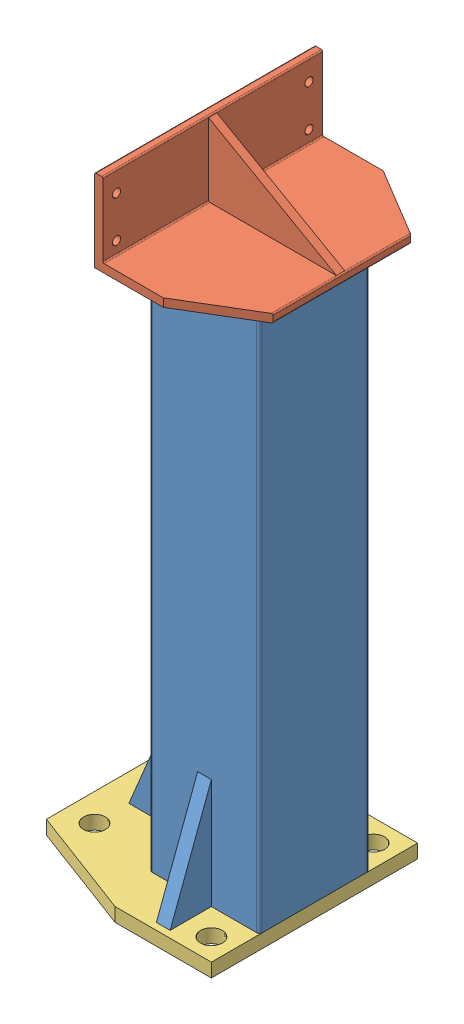
SolidWorks assembly chan1, configuration Default. Lengths in mm.
Overall size (170 470 160).
3 component instances, 3 part files, 6 mates.
Components (placement in the parent):
- hop 80x80x4xL400-1: hop 80x80x4xL400 [Default] at (-21.5992 70.0166 491.4682) size (130 400 140)
- bich1-1: bich1 [Default] at (-21.5992 470.0166 371.4682) x (1 0 0) z (0 -1 0) size (100 160 60)
- bichchan-1: bichchan [Default] at (-91.5992 60.0166 526.4682) size (150 10 150)
Mates (geometry in assembly coordinates):
- Coincident1: coincident anti-aligned: plane of hop 80x80x4xL400-1 through (-19.5992 470.0166 489.4682) normal (0 1 0); plane of bich1-1 through (77.4008 470.0166 531.4682) normal (0 -1 0)
- Coincident2: coincident anti-aligned: line of hop 80x80x4xL400-1 through (-21.5992 470.0166 413.4682) axis (0 0 1); line of bich1-1 through (-21.5992 470.0166 531.4682) axis (0 0 -1)
- Coincident3: coincident: point of hop 80x80x4xL400-1; unknown of bich1-1
- Coincident4: coincident anti-aligned: plane of hop 80x80x4xL400-1 through (-19.5992 70.0166 489.4682) normal (0 -1 0); plane of bichchan-1 through (-91.5992 70.0166 526.4682) normal (0 1 0)
- Coincident5: coincident: unknown of hop 80x80x4xL400-1; unknown of bichchan-1
- Coincident6: coincident aligned: line of hop 80x80x4xL400-1 through (58.4008 70.0166 489.4682) axis (0 0 -1); line of bichchan-1 through (58.4008 70.0166 526.4682) axis (0 0 -1)
